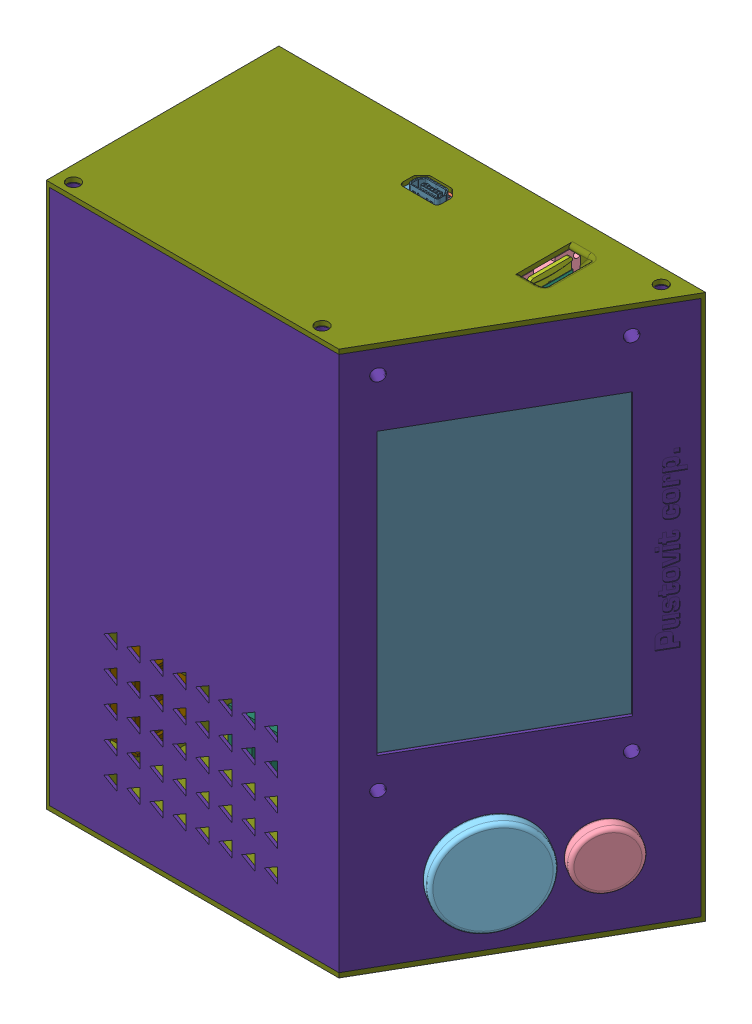
SolidWorks assembly computer, configuration Default. Lengths in mm.
Overall size (117.11 142.67 60.8).
166 component instances, 59 part files, 42 mates.
Components (placement in the parent):
- Arduino Sensor Board V1-1: Arduino Sensor Board V1 [По умолчанию] at (-9.625 26.58 9.294) x (-1 0 0) z (0 1 0) size (53.65 20.91 58.16)
- NUCLEO-F4-1: NUCLEO-F4 [По умолчанию] at origin size (70 83.97 20.27)
  - NUCLEO-F411RE_PCB_VarsayВЌlan-1: NUCLEO-F411RE_PCB_VarsayВЌlan [По умолчанию] at origin size (70 82.5 1.5)
  - NUCLEO-F411RE_PCB_HOLEs_VarsayВЌlan-1: NUCLEO-F411RE_PCB_HOLEs_VarsayВЌlan [По умолчанию] at origin size (65.28 79.87 1.57)
  - NUCLEO-F411RE_PCB_TOP_Pads_VarsayВЌlan-1: NUCLEO-F411RE_PCB_TOP_Pads_VarsayВЌlan [По умолчанию] at origin size (59.94 77.1 0.04)
  - NUCLEO-F411RE_PCB_TOP_Solder_VarsayВЌlan-1: NUCLEO-F411RE_PCB_TOP_Solder_VarsayВЌlan [По умолчанию] at origin size (69.8 82.3 0.05)
  - NUCLEO-F411RE_PCB_BOTTOM_Pads_VarsayВЌlan-1: NUCLEO-F411RE_PCB_BOTTOM_Pads_VarsayВЌlan [По умолчанию] at origin size (31.1 70.87 0.04)
  - NUCLEO-F411RE_PCB_BOTTOM_Solder_VarsayВЌlan-1: NUCLEO-F411RE_PCB_BOTTOM_Solder_VarsayВЌlan [По умолчанию] at origin size (69.8 82.3 0.04)
  - NUCLEO-F411RE_PCB_TOP_Overlay_VarsayВЌlan-1: NUCLEO-F411RE_PCB_TOP_Overlay_VarsayВЌlan [По умолчанию] at origin size (68.11 77.69 0.03)
  - NUCLEO-F411RE_PCB_TOP_Designators_VarsayВЌlan-1: NUCLEO-F411RE_PCB_TOP_Designators_VarsayВЌlan [По умолчанию] at origin size (66.31 79.66 0.03)
  - NUCLEO-F411RE_PCB_BOTTOM_Overlay_VarsayВЌlan-1: NUCLEO-F411RE_PCB_BOTTOM_Overlay_VarsayВЌlan [По умолчанию] at origin size (40.14 80.79 0.03)
  - SAMTEC_SSQ-106-01-G-S_for_NUCLEO_VarsayВЌlan-1: SAMTEC_SSQ-106-01-G-S_for_NUCLEO_VarsayВЌlan [По умолчанию] at (-33.02 8.89 0.785) x (0 1 0) z (1 0 0) size (15.75 11.15 2.41)
  - SAMTEC_SSQ-108-01-G-S_for_NUCLEO_VarsayВЌlan-1: SAMTEC_SSQ-108-01-G-S_for_NUCLEO_VarsayВЌlan [По умолчанию] at (-33.02 29.21 0.785) x (0 1 0) z (1 0 0) size (20.83 11.15 2.41)
  - SAMTEC_SSQ-110-01-G-S_for_NUCLEO_VarsayВЌlan-1: SAMTEC_SSQ-110-01-G-S_for_NUCLEO_VarsayВЌlan [По умолчанию] at (15.24 35.814 0.785) x (0 1 0) z (1 0 0) size (25.91 11.15 2.41)
  - MOLEX_0678038020_for_NUCLEO-1: MOLEX_0678038020_for_NUCLEO [По умолчанию] at (3.1721 75.2975 0.785) x (-1 0 0) z (0 1 0) size (9.9 4.95 9)
  - SAMTEC_TSW-119-07-T-D_for_NUCLEO_VarsayВЌlan-1: SAMTEC_TSW-119-07-T-D_for_NUCLEO_VarsayВЌlan [По умолчанию] at (-39.37 25.4 0.785) x (0 -1 0) z (-1 0 0) size (48.26 17.95 5.08)
  - SAMTEC_TSW-102-07-T-S_for_NUCLEO_VarsayВЌlan-1: SAMTEC_TSW-102-07-T-S_for_NUCLEO_VarsayВЌlan [По умолчанию] at (-40.64 74.93 0.785) x (0 1 0) z (1 0 0) size (5.08 10.92 2.54)
  - SAMTEC_TSW-103-07-T-S_for_NUCLEO_VarsayВЌlan-1: SAMTEC_TSW-103-07-T-S_for_NUCLEO_VarsayВЌlan [По умолчанию] at (1.905 45.085 0.785) x (1 0 0) z (0 -1 0) size (7.62 10.92 2.54)
  - SAMTEC_TSW-104-07-T-S_for_NUCLEO_VarsayВЌlan-1: SAMTEC_TSW-104-07-T-S_for_NUCLEO_VarsayВЌlan [По умолчанию] at (-21.59 73.66 0.785) x (0 1 0) z (1 0 0) size (10.16 10.92 2.54)
  - SAMTEC_TSW-106-07-T-S_for_NUCLEO_VarsayВЌlan-1: SAMTEC_TSW-106-07-T-S_for_NUCLEO_VarsayВЌlan [По умолчанию] at (-35.56 64.77 0.785) x (0 1 0) z (1 0 0) size (15.24 10.92 2.54)
  - MOLEX_90059-0007-1: MOLEX_90059-0007 [По умолчанию] at (-21.59 76.2 5.75) x (0 1 0) z (1 0 0) size (5.1 4.85 2.54)
  - ST_STM32F411RET6_VarsayВЌlan-1: ST_STM32F411RET6_VarsayВЌlan [По умолчанию] at (-11.4265 21.5935 0.785) x (-1 0 0) z (0 0 -1) size (12 12 1.61)
  - ST_STM32F103CBT6_VarsayВЌlan-1: ST_STM32F103CBT6_VarsayВЌlan [По умолчанию] at (-8.89 64.77 0.785) x (1 0 0) z (0 -1 0) size (9 1.61 9)
  - ESWITCH_TL3301SPF160QGBLK_VarsayВЌlan-1: ESWITCH_TL3301SPF160QGBLK_VarsayВЌlan [По умолчанию] at (-0.635 50.8 0.785) x (0 -1 0) z (-1 0 0) size (6.01 10.7 10)
  - ESWITCH_TL3301SPF160QGBLU_VarsayВЌlan-1: ESWITCH_TL3301SPF160QGBLU_VarsayВЌlan [По умолчанию] at (-17.145 50.8 0.785) x (0 1 0) z (1 0 0) size (6.01 10.7 10)
  - ST_STS7PF30L_VarsayВЌlan-1: ST_STS7PF30L_VarsayВЌlan [По умолчанию] at (17.145 60.325 0.785) x (-1 0 0) z (0 1 0) size (4.91 1.76 6)
  - ABRACON_ABL-8-1: ABRACON_ABL-8 [По умолчанию] at (-18.41 63.4908 0.785) x (0 -1 0) z (-1 0 0) size (11.5 5.59 5)
  - ST_LD1117S50TR_VarsayВЌlan-1: ST_LD1117S50TR_VarsayВЌlan [По умолчанию] at (-14.6685 43.18 0.785) x (0 -1 0) z (-1 0 0) size (6.51 1.91 7)
  - ST_LD39050PU33R_VarsayВЌlan-1: ST_LD39050PU33R_VarsayВЌlan [По умолчанию] at (1.905 40.64 0.785) x (0 1 0) z (1 0 0) size (3.01 1.01 3.01)
  - ST_LD3985M33R_VarsayВЌlan-1: ST_LD3985M33R_VarsayВЌlan [По умолчанию] at (7.62 63.5 0.785) x (1 0 0) z (0 -1 0) size (2.96 1.46 2.8)
  - KEMET_T491B106K025AT_VarsayВЌlan-1: KEMET_T491B106K025AT_VarsayВЌlan [По умолчанию] at (-22.86 41.275 0.785) x (0 -1 0) z (-1 0 0) size (2.81 1.91 3.5)
  - ST_STPS2L30A_VarsayВЌlan-1: ST_STPS2L30A_VarsayВЌlan [По умолчанию] at (-22.86 45.085 0.785) x (0 1 0) z (1 0 0) size (2.59 2.31 5.07)
  - KEMET_T491A106K006AT7280_VarsayВЌlan-1: KEMET_T491A106K006AT7280_VarsayВЌlan [По умолчанию] at (-8.255 43.053 0.785) x (1 0 0) z (0 -1 0) size (1.61 1.61 3.2)
  - ABRACON_ABS25-32-1: ABRACON_ABS25-32 [По умолчанию] at (-23.495 6.35 0.785) x (1 0 0) z (0 -1 0) size (8 2.67 4)
  - LUMEX_SML-LX2835IGC-TR-1: LUMEX_SML-LX2835IGC-TR [По умолчанию] at (16.51 73.66 0.785) x (1 0 0) z (0 -1 0) size (2.7 1.8 3.5)
  - ST_BAT60JFILM_VarsayВЌlan-1: ST_BAT60JFILM_VarsayВЌlan [По умолчанию] at (-31.115 71.12 0.785) x (0 -1 0) z (-1 0 0) size (1.29 1.18 2.5)
  - NXP_BC847B,215-1: NXP_BC847B,215 [По умолчанию] at (12.065 64.135 0.785) x (0 -1 0) z (-1 0 0) size (2.9 1.11 2.43)
  - YAGEO_CC0805KKX7R7BB225-1: YAGEO_CC0805KKX7R7BB225 [По умолчанию] at (0.127 23.495 0.785) x (0 -1 0) z (-1 0 0) size (1.59 1.29 4.06)
  - YAGEO_RC0603JR-070RL-1: YAGEO_RC0603JR-070RL [По умолчанию] at (17.145 67.945 0.785) x (1 0 0) z (0 -1 0) size (0.8 0.55 2.16)
  - YAGEO_CC0603KRX7R7BB104-1: YAGEO_CC0603KRX7R7BB104 [По умолчанию] at (-11.43 73.025 0.785) x (1 0 0) z (0 -1 0) size (0.8 0.8 2.16)
  - SAMTEC_SSQ-108-01-G-S_for_NUCLEO_VarsayВЌlan-2: SAMTEC_SSQ-108-01-G-S_for_NUCLEO_VarsayВЌlan [По умолчанию] at (15.24 11.43 0.785) x (0 1 0) z (1 0 0) size (20.83 11.15 2.41)
  - SAMTEC_TSW-119-07-T-D_for_NUCLEO_VarsayВЌlan-2: SAMTEC_TSW-119-07-T-D_for_NUCLEO_VarsayВЌlan [По умолчанию] at (21.59 25.4 0.785) x (0 -1 0) z (-1 0 0) size (48.26 17.95 5.08)
  - SAMTEC_TSW-102-07-T-S_for_NUCLEO_VarsayВЌlan-2: SAMTEC_TSW-102-07-T-S_for_NUCLEO_VarsayВЌlan [По умолчанию] at (-31.75 59.055 0.785) x (0 -1 0) z (-1 0 0) size (5.08 10.92 2.54)
  - SAMTEC_TSW-102-07-T-S_for_NUCLEO_VarsayВЌlan-3: SAMTEC_TSW-102-07-T-S_for_NUCLEO_VarsayВЌlan [По умолчанию] at (-9.525 77.47 0.785) x (1 0 0) z (0 -1 0) size (5.08 10.92 2.54)
  - SAMTEC_TSW-102-07-T-S_for_NUCLEO_VarsayВЌlan-4: SAMTEC_TSW-102-07-T-S_for_NUCLEO_VarsayВЌlan [По умолчанию] at (-9.525 38.735 0.785) x (1 0 0) z (0 -1 0) size (5.08 10.92 2.54)
  - SAMTEC_TSW-102-07-T-S_for_NUCLEO_VarsayВЌlan-5: SAMTEC_TSW-102-07-T-S_for_NUCLEO_VarsayВЌlan [По умолчанию] at (22.86 74.93 0.785) x (0 -1 0) z (-1 0 0) size (5.08 10.92 2.54)
  - MOLEX_90059-0007-2: MOLEX_90059-0007 [По умолчанию] at (-21.59 71.12 5.75) x (0 -1 0) z (-1 0 0) size (5.1 4.85 2.54)
  - MOLEX_90059-0007-3: MOLEX_90059-0007 [По умолчанию] at (3.175 45.085 5.75) x (-1 0 0) z (0 1 0) size (5.1 4.85 2.54)
  - ST_BAT60JFILM_VarsayВЌlan-2: ST_BAT60JFILM_VarsayВЌlan [По умолчанию] at (7.62 69.85 0.785) x (0 -1 0) z (-1 0 0) size (1.29 1.18 2.5)
  - ST_BAT60JFILM_VarsayВЌlan-3: ST_BAT60JFILM_VarsayВЌlan [По умолчанию] at (10.795 59.69 0.785) x (1 0 0) z (0 -1 0) size (1.29 1.18 2.5)
  - YAGEO_RC0603JR-070RL-2: YAGEO_RC0603JR-070RL [По умолчанию] at (15.875 67.945 0.785) x (1 0 0) z (0 -1 0) size (0.8 0.55 2.16)
  - YAGEO_RC0603JR-070RL-3: YAGEO_RC0603JR-070RL [По умолчанию] at (14.605 67.945 0.785) x (1 0 0) z (0 -1 0) size (0.8 0.55 2.16)
  - YAGEO_RC0603JR-070RL-4: YAGEO_RC0603JR-070RL [По умолчанию] at (13.335 67.945 0.785) x (1 0 0) z (0 -1 0) size (0.8 0.55 2.16)
  - YAGEO_RC0603JR-070RL-5: YAGEO_RC0603JR-070RL [По умолчанию] at (12.065 67.945 0.785) x (1 0 0) z (0 -1 0) size (0.8 0.55 2.16)
  - YAGEO_RC0603JR-070RL-6: YAGEO_RC0603JR-070RL [По умолчанию] at (10.795 67.945 0.785) x (1 0 0) z (0 -1 0) size (0.8 0.55 2.16)
  - YAGEO_RC0603JR-070RL-7: YAGEO_RC0603JR-070RL [По умолчанию] at (12.7 59.7535 0.785) x (1 0 0) z (0 -1 0) size (0.8 0.55 2.16)
  - YAGEO_RC0603JR-070RL-8: YAGEO_RC0603JR-070RL [По умолчанию] at (4.445 67.945 0.785) x (1 0 0) z (0 -1 0) size (0.8 0.55 2.16)
  - YAGEO_RC0603JR-070RL-9: YAGEO_RC0603JR-070RL [По умолчанию] at (3.175 67.945 0.785) x (1 0 0) z (0 -1 0) size (0.8 0.55 2.16)
  - YAGEO_RC0603JR-070RL-10: YAGEO_RC0603JR-070RL [По умолчанию] at (1.905 67.945 0.785) x (1 0 0) z (0 -1 0) size (0.8 0.55 2.16)
  - YAGEO_RC0603JR-070RL-11: YAGEO_RC0603JR-070RL [По умолчанию] at (0 67.945 0.785) x (1 0 0) z (0 -1 0) size (0.8 0.55 2.16)
  - YAGEO_RC0603JR-070RL-12: YAGEO_RC0603JR-070RL [По умолчанию] at (-6.985 73.025 0.785) x (1 0 0) z (0 -1 0) size (0.8 0.55 2.16)
  - YAGEO_RC0603JR-070RL-13: YAGEO_RC0603JR-070RL [По умолчанию] at (-8.255 73.025 0.785) x (1 0 0) z (0 -1 0) size (0.8 0.55 2.16)
  - YAGEO_RC0603JR-070RL-14: YAGEO_RC0603JR-070RL [По умолчанию] at (-9.525 73.025 0.785) x (1 0 0) z (0 -1 0) size (0.8 0.55 2.16)
  - YAGEO_RC0603JR-070RL-15: YAGEO_RC0603JR-070RL [По умолчанию] at (-14.605 73.025 0.785) x (1 0 0) z (0 -1 0) size (0.8 0.55 2.16)
  - YAGEO_RC0603JR-070RL-16: YAGEO_RC0603JR-070RL [По умолчанию] at (-31.115 73.025 0.785) x (0 -1 0) z (-1 0 0) size (0.8 0.55 2.16)
  - YAGEO_RC0603JR-070RL-17: YAGEO_RC0603JR-070RL [По умолчанию] at (-31.115 69.215 0.785) x (0 -1 0) z (-1 0 0) size (0.8 0.55 2.16)
  - YAGEO_RC0603JR-070RL-18: YAGEO_RC0603JR-070RL [По умолчанию] at (-31.115 67.31 0.785) x (0 -1 0) z (-1 0 0) size (0.8 0.55 2.16)
  - YAGEO_RC0603JR-070RL-19: YAGEO_RC0603JR-070RL [По умолчанию] at (-31.115 65.405 0.785) x (0 -1 0) z (-1 0 0) size (0.8 0.55 2.16)
  - YAGEO_RC0603JR-070RL-20: YAGEO_RC0603JR-070RL [По умолчанию] at (-31.115 63.5 0.785) x (0 -1 0) z (-1 0 0) size (0.8 0.55 2.16)
  - YAGEO_RC0603JR-070RL-21: YAGEO_RC0603JR-070RL [По умолчанию] at (-25.4 64.77 0.785) x (0 -1 0) z (-1 0 0) size (0.8 0.55 2.16)
  - YAGEO_RC0603JR-070RL-22: YAGEO_RC0603JR-070RL [По умолчанию] at (-25.4 63.5 0.785) x (0 -1 0) z (-1 0 0) size (0.8 0.55 2.16)
  - YAGEO_RC0603JR-070RL-23: YAGEO_RC0603JR-070RL [По умолчанию] at (-25.4 62.23 0.785) x (0 -1 0) z (-1 0 0) size (0.8 0.55 2.16)
  - YAGEO_RC0603JR-070RL-24: YAGEO_RC0603JR-070RL [По умолчанию] at (-25.4 60.96 0.785) x (0 -1 0) z (-1 0 0) size (0.8 0.55 2.16)
  - YAGEO_RC0603JR-070RL-25: YAGEO_RC0603JR-070RL [По умолчанию] at (-15.875 11.43 0.785) x (1 0 0) z (0 -1 0) size (0.8 0.55 2.16)
  - YAGEO_RC0603JR-070RL-26: YAGEO_RC0603JR-070RL [По умолчанию] at (-14.605 11.43 0.785) x (1 0 0) z (0 -1 0) size (0.8 0.55 2.16)
  - YAGEO_RC0603JR-070RL-27: YAGEO_RC0603JR-070RL [По умолчанию] at (-22.225 18.415 0.785) x (1 0 0) z (0 -1 0) size (0.8 0.55 2.16)
  - YAGEO_RC0603JR-070RL-28: YAGEO_RC0603JR-070RL [По умолчанию] at (-20.955 32.385 0.785) x (0 -1 0) z (-1 0 0) size (0.8 0.55 2.16)
  - YAGEO_RC0603JR-070RL-29: YAGEO_RC0603JR-070RL [По умолчанию] at (-8.89 51.435 0.785) x (0 -1 0) z (-1 0 0) size (0.8 0.55 2.16)
  - YAGEO_RC0603JR-070RL-30: YAGEO_RC0603JR-070RL [По умолчанию] at (-8.89 47.625 0.785) x (0 -1 0) z (-1 0 0) size (0.8 0.55 2.16)
  - YAGEO_RC0603JR-070RL-31: YAGEO_RC0603JR-070RL [По умолчанию] at (3.81 36.83 0.785) x (0 -1 0) z (-1 0 0) size (0.8 0.55 2.16)
  - YAGEO_RC0603JR-070RL-32: YAGEO_RC0603JR-070RL [По умолчанию] at (0 63.5 0.785) x (0 -1 0) z (-1 0 0) size (0.8 0.55 2.16)
  - YAGEO_RC0603JR-070RL-33: YAGEO_RC0603JR-070RL [По умолчанию] at (0 62.23 0.785) x (0 -1 0) z (-1 0 0) size (0.8 0.55 2.16)
  - YAGEO_CC0603KRX7R7BB104-2: YAGEO_CC0603KRX7R7BB104 [По умолчанию] at (-1.905 67.945 0.785) x (1 0 0) z (0 -1 0) size (0.8 0.8 2.16)
  - YAGEO_CC0603KRX7R7BB104-3: YAGEO_CC0603KRX7R7BB104 [По умолчанию] at (5.08 62.865 0.785) x (1 0 0) z (0 -1 0) size (0.8 0.8 2.16)
  - YAGEO_CC0603KRX7R7BB104-4: YAGEO_CC0603KRX7R7BB104 [По умолчанию] at (6.985 59.69 0.785) x (1 0 0) z (0 -1 0) size (0.8 0.8 2.16)
  - YAGEO_CC0603KRX7R7BB104-5: YAGEO_CC0603KRX7R7BB104 [По умолчанию] at (8.89 59.69 0.785) x (1 0 0) z (0 -1 0) size (0.8 0.8 2.16)
  - YAGEO_CC0603KRX7R7BB104-6: YAGEO_CC0603KRX7R7BB104 [По умолчанию] at (-21.59 62.23 0.785) x (1 0 0) z (0 -1 0) size (0.8 0.8 2.16)
  - YAGEO_CC0603KRX7R7BB104-7: YAGEO_CC0603KRX7R7BB104 [По умолчанию] at (-21.59 64.77 0.785) x (1 0 0) z (0 -1 0) size (0.8 0.8 2.16)
  - YAGEO_CC0603KRX7R7BB104-8: YAGEO_CC0603KRX7R7BB104 [По умолчанию] at (-15.24 63.5 0.785) x (1 0 0) z (0 -1 0) size (0.8 0.8 2.16)
  - YAGEO_CC0603KRX7R7BB104-9: YAGEO_CC0603KRX7R7BB104 [По умолчанию] at (-6.35 58.42 0.785) x (0 -1 0) z (-1 0 0) size (0.8 0.8 2.16)
  - YAGEO_CC0603KRX7R7BB104-10: YAGEO_CC0603KRX7R7BB104 [По умолчанию] at (-8.89 53.34 0.785) x (0 -1 0) z (-1 0 0) size (0.8 0.8 2.16)
  - YAGEO_CC0603KRX7R7BB104-11: YAGEO_CC0603KRX7R7BB104 [По умолчанию] at (-8.89 49.53 0.785) x (0 -1 0) z (-1 0 0) size (0.8 0.8 2.16)
  - YAGEO_CC0603KRX7R7BB104-12: YAGEO_CC0603KRX7R7BB104 [По умолчанию] at (-2.54 40.64 0.785) x (1 0 0) z (0 -1 0) size (0.8 0.8 2.16)
  - YAGEO_CC0603KRX7R7BB104-13: YAGEO_CC0603KRX7R7BB104 [По умолчанию] at (-1.27 40.64 0.785) x (1 0 0) z (0 -1 0) size (0.8 0.8 2.16)
  - YAGEO_CC0603KRX7R7BB104-14: YAGEO_CC0603KRX7R7BB104 [По умолчанию] at (5.08 40.64 0.785) x (1 0 0) z (0 -1 0) size (0.8 0.8 2.16)
  - YAGEO_CC0603KRX7R7BB104-15: YAGEO_CC0603KRX7R7BB104 [По умолчанию] at (6.35 40.64 0.785) x (1 0 0) z (0 -1 0) size (0.8 0.8 2.16)
  - YAGEO_CC0603KRX7R7BB104-16: YAGEO_CC0603KRX7R7BB104 [По умолчанию] at (-0.6033 27.94 0.785) x (0 -1 0) z (-1 0 0) size (0.8 0.8 2.16)
  - YAGEO_CC0603KRX7R7BB104-17: YAGEO_CC0603KRX7R7BB104 [По умолчанию] at (-17.145 32.385 0.785) x (1 0 0) z (0 -1 0) size (0.8 0.8 2.16)
  - YAGEO_CC0603KRX7R7BB104-18: YAGEO_CC0603KRX7R7BB104 [По умолчанию] at (-20.32 18.415 0.785) x (1 0 0) z (0 -1 0) size (0.8 0.8 2.16)
  - YAGEO_CC0603KRX7R7BB104-19: YAGEO_CC0603KRX7R7BB104 [По умолчанию] at (-17.145 11.43 0.785) x (1 0 0) z (0 -1 0) size (0.8 0.8 2.16)
  - YAGEO_CC0603KRX7R7BB104-20: YAGEO_CC0603KRX7R7BB104 [По умолчанию] at (0 17.78 0.785) x (0 -1 0) z (-1 0 0) size (0.8 0.8 2.16)
  - YAGEO_CC0603KRX7R7BB104-21: YAGEO_CC0603KRX7R7BB104 [По умолчанию] at (-8.636 12.192 0.785) x (0 -1 0) z (-1 0 0) size (0.8 0.8 2.16)
  - YAGEO_CC0603KRX7R7BB104-22: YAGEO_CC0603KRX7R7BB104 [По умолчанию] at (-19.685 2.794 0.785) x (0 -1 0) z (-1 0 0) size (0.8 0.8 2.16)
  - YAGEO_CC0603KRX7R7BB104-23: YAGEO_CC0603KRX7R7BB104 [По умолчанию] at (-19.685 10.795 0.785) x (0 -1 0) z (-1 0 0) size (0.8 0.8 2.16)
- Product_TF Micro SD Card Memory Modul Arduino-1: Product_TF Micro SD Card Memory Modul Arduino [Default] at (32.8 80 5.215) x (0 0 1) z (1 0 0) size (24 45.73 7.3)
  - PCB-1: PCB [По умолчанию] at origin size (24 41.8 1.25)
  - 1 Pin 2.54 mm Right Angle Single Row Pin Header Male 90 degrees Needle Connector-1: 1 Pin 2.54 mm Right Angle Single Row Pin Header Male 90 degrees Needle Connector [По умолчанию] at (-6.375 38.55 -1.71) x (0 1 0) z (0 0 1) size (8.45 2.54 7.3)
  - 1 Pin 2.54 mm Right Angle Single Row Pin Header Male 90 degrees Needle Connector-2: 1 Pin 2.54 mm Right Angle Single Row Pin Header Male 90 degrees Needle Connector [По умолчанию] at (-3.835 38.55 -1.71) x (0 1 0) z (0 0 1) size (8.45 2.54 7.3)
  - 1 Pin 2.54 mm Right Angle Single Row Pin Header Male 90 degrees Needle Connector-3: 1 Pin 2.54 mm Right Angle Single Row Pin Header Male 90 degrees Needle Connector [По умолчанию] at (-1.295 38.55 -1.71) x (0 1 0) z (0 0 1) size (8.45 2.54 7.3)
  - 1 Pin 2.54 mm Right Angle Single Row Pin Header Male 90 degrees Needle Connector-4: 1 Pin 2.54 mm Right Angle Single Row Pin Header Male 90 degrees Needle Connector [По умолчанию] at (1.245 38.55 -1.71) x (0 1 0) z (0 0 1) size (8.45 2.54 7.3)
  - 1 Pin 2.54 mm Right Angle Single Row Pin Header Male 90 degrees Needle Connector-5: 1 Pin 2.54 mm Right Angle Single Row Pin Header Male 90 degrees Needle Connector [По умолчанию] at (3.785 38.55 -1.71) x (0 1 0) z (0 0 1) size (8.45 2.54 7.3)
  - 1 Pin 2.54 mm Right Angle Single Row Pin Header Male 90 degrees Needle Connector-6: 1 Pin 2.54 mm Right Angle Single Row Pin Header Male 90 degrees Needle Connector [По умолчанию] at (6.325 38.55 -1.71) x (0 1 0) z (0 0 1) size (8.45 2.54 7.3)
  - slot-1: slot [По умолчанию] at (-0.1 9.44 2.1) size (16 15 2.44)
  - sd-1: sd [По умолчанию] at (-45.7851 11.4225 2.13) size (11 15 1.1)
  - nano - reg-1: nano - reg [По умолчанию] at (5.85 28.63 1.25) x (0 -1 0) z (-1 0 0) size (6.5 1.69 8.3)
  - res_603-1: res_603 [По умолчанию] at (-9.4 21.6 1.25) x (0 -1 0) z (-1 0 0) size (1.6 0.5 0.8)
  - res_603-2: res_603 [По умолчанию] at (-7.35 21.6 1.25) x (0 -1 0) z (-1 0 0) size (1.6 0.5 0.8)
  - res_603-3: res_603 [По умолчанию] at (-7.3 34.3 1.25) x (0 -1 0) z (-1 0 0) size (1.6 0.5 0.8)
  - res_603-4: res_603 [По умолчанию] at (-8.8 34.3 1.25) x (0 -1 0) z (-1 0 0) size (1.6 0.5 0.8)
  - cap_603-1: cap_603 [По умолчанию] at (-9.34 32.2 2.05) x (0 1 0) z (0 0 1) size (1.6 0.8 0.8)
  - cap_603-2: cap_603 [По умолчанию] at (7.2 20.55 2.05) x (0 1 0) z (0 0 1) size (1.6 0.8 0.8)
  - cap_603-3: cap_603 [По умолчанию] at (10.8 33.9 2.05) x (0 1 0) z (0 0 1) size (1.6 0.8 0.8)
  - cap_805-1: cap_805 [По умолчанию] at (9.4 20.1 2.05) x (0 1 0) z (0 0 1) size (2.06 1.35 0.82)
  - LVC125A-1: LVC125A [По умолчанию] at (-10.3 28.9 1.25) x (0 -1 0) z (0 0 1) size (6.6 5.2 0.95)
- DIN 5 Connector (Female)-1: DIN 5 Connector (Female) [По умолчанию] at (-50.3 -11.2 32.415) x (0 -1 0) z (-1 0 0) size (29 18.3 17)
- Pantalla Nextion 3.5-1: Pantalla Nextion 3.5 [По умолчанию] at (37.9033 26.95 20.4374) x (0 -1 0) z (0.866025 0 0.5) size (100.5 54.94 11.65)
- DC-DC CC CV Buck Converter Step-down Power Supply Module 7-40V to 1-35V 12A-1: DC-DC CC CV Buck Converter Step-down Power Supply Module 7-40V to 1-35V 12A [00] at (-8 -30 0.715) x (0 -1 0) z (-1 0 0) size (49 24 65)
- Корпус база^computer-1: Корпус база^computer [По умолчанию] at origin size (111.6 142.4 60.8) (virtual)
- Корпус крышка^computer-1: Корпус крышка^computer [По умолчанию] at (0 -61.2 0) x (-1 0 0) z (0 -1 0) size (110.34 60 140) (virtual)
- Power Switch-1: Power Switch [По умолчанию] at (-48.8 -51.2 40.415) x (0 1 0) z (0 0 1) size (21.33 24.14 14.86)
- Pins_place-1: Pins_place [Default] at (-40 43 30.215) x (0 1 0) z (0 0 1) size (70 10.84 30)
  - PIN-1: PIN [По умолчанию] at (24.34 2 3.88) x (0 0 -1) z (1 0 0) size (2.54 10.84 2.54)
  - place-1: place [По умолчанию] at origin size (70 2 30)
  - PIN-2: PIN [По умолчанию] at (24.34 2 1.34) x (0 0 -1) z (1 0 0) size (2.54 10.84 2.54)
  - PIN-3: PIN [По умолчанию] at (24.34 2 -1.2) x (0 0 -1) z (1 0 0) size (2.54 10.84 2.54)
  - PIN-4: PIN [По умолчанию] at (21.8 2 3.88) x (0 0 -1) z (1 0 0) size (2.54 10.84 2.54)
  - PIN-5: PIN [По умолчанию] at (21.8 2 1.34) x (0 0 -1) z (1 0 0) size (2.54 10.84 2.54)
  - PIN-6: PIN [По умолчанию] at (21.8 2 -1.2) x (0 0 -1) z (1 0 0) size (2.54 10.84 2.54)
  - PIN-7: PIN [По умолчанию] at (19.26 2 3.88) x (0 0 -1) z (1 0 0) size (2.54 10.84 2.54)
  - PIN-8: PIN [По умолчанию] at (19.26 2 1.34) x (0 0 -1) z (1 0 0) size (2.54 10.84 2.54)
  - PIN-9: PIN [По умолчанию] at (19.26 2 -1.2) x (0 0 -1) z (1 0 0) size (2.54 10.84 2.54)
  - PIN-10: PIN [По умолчанию] at (16.72 2 3.88) x (0 0 -1) z (1 0 0) size (2.54 10.84 2.54)
  - PIN-11: PIN [По умолчанию] at (16.72 2 1.34) x (0 0 -1) z (1 0 0) size (2.54 10.84 2.54)
  - PIN-12: PIN [По умолчанию] at (16.72 2 -1.2) x (0 0 -1) z (1 0 0) size (2.54 10.84 2.54)
  - PIN-13: PIN [По умолчанию] at (14.18 2 3.88) x (0 0 -1) z (1 0 0) size (2.54 10.84 2.54)
  - PIN-14: PIN [По умолчанию] at (14.18 2 1.34) x (0 0 -1) z (1 0 0) size (2.54 10.84 2.54)
  - PIN-15: PIN [По умолчанию] at (14.18 2 -1.2) x (0 0 -1) z (1 0 0) size (2.54 10.84 2.54)
  - PIN-16: PIN [По умолчанию] at (11.64 2 3.88) x (0 0 -1) z (1 0 0) size (2.54 10.84 2.54)
  - PIN-17: PIN [По умолчанию] at (11.64 2 1.34) x (0 0 -1) z (1 0 0) size (2.54 10.84 2.54)
  - PIN-18: PIN [По умолчанию] at (11.64 2 -1.2) x (0 0 -1) z (1 0 0) size (2.54 10.84 2.54)
  - PIN-19: PIN [По умолчанию] at (9.1 2 3.88) x (0 0 -1) z (1 0 0) size (2.54 10.84 2.54)
  - PIN-20: PIN [По умолчанию] at (9.1 2 1.34) x (0 0 -1) z (1 0 0) size (2.54 10.84 2.54)
  - PIN-21: PIN [По умолчанию] at (9.1 2 -1.2) x (0 0 -1) z (1 0 0) size (2.54 10.84 2.54)
  - PIN-22: PIN [По умолчанию] at (6.56 2 3.88) x (0 0 -1) z (1 0 0) size (2.54 10.84 2.54)
  - PIN-23: PIN [По умолчанию] at (6.56 2 1.34) x (0 0 -1) z (1 0 0) size (2.54 10.84 2.54)
  - PIN-24: PIN [По умолчанию] at (6.56 2 -1.2) x (0 0 -1) z (1 0 0) size (2.54 10.84 2.54)
  - PIN-25: PIN [По умолчанию] at (4.02 2 3.88) x (0 0 -1) z (1 0 0) size (2.54 10.84 2.54)
  - PIN-26: PIN [По умолчанию] at (4.02 2 1.34) x (0 0 -1) z (1 0 0) size (2.54 10.84 2.54)
  - PIN-27: PIN [По умолчанию] at (4.02 2 -1.2) x (0 0 -1) z (1 0 0) size (2.54 10.84 2.54)
  - PIN-28: PIN [По умолчанию] at (1.48 2 3.88) x (0 0 -1) z (1 0 0) size (2.54 10.84 2.54)
  - PIN-29: PIN [По умолчанию] at (1.48 2 1.34) x (0 0 -1) z (1 0 0) size (2.54 10.84 2.54)
  - PIN-30: PIN [По умолчанию] at (1.48 2 -1.2) x (0 0 -1) z (1 0 0) size (2.54 10.84 2.54)
- Button-1: Button [По умолчанию] at (48.508 -41 5.1695) x (0 -1 0) z (-0.5 0 0.866025) size (14.38 11.2 12)
- Button-2: Button [По умолчанию] at (37.508 -41 24.222) x (0 1 0) z (0.5 0 -0.866025) size (14.38 11.2 12)
- ResetBut-1: ResetBut [По умолчанию] at (56.7785 -41 9.9445) x (0 -1 0) z (-0.5 0 0.866025) size (15 5 15)
- StopBut-1: StopBut [По умолчанию] at (45.7785 -41 28.997) x (0 -1 0) z (-0.5 0 0.866025) size (25 5 25)
Mates (geometry in assembly coordinates):
- Совпадение2: coincident anti-aligned: plane of Arduino Sensor Board V1-1 through (-9.6294 26.9555 9.294) normal (0 0 -1); plane of NUCLEO-F4-1/SAMTEC_SSQ-108-01-G-S_for_NUCLEO_VarsayВЌlan-2 through (14.0235 1.006 9.294) normal (0 0 1)
- Концентричный1: concentric aligned: cylinder of Arduino Sensor Board V1-1 through (0 0 9.294) axis (0 0 1) radius 1.75; circle of NUCLEO-F4-1/NUCLEO-F411RE_PCB_HOLEs_VarsayВЌlan-1
- Параллельность1: parallel anti-aligned: plane of Arduino Sensor Board V1-1 through (-34.37 2.11 9.294) normal (-1 0 0); plane of NUCLEO-F4-1/SAMTEC_SSQ-106-01-G-S_for_NUCLEO_VarsayВЌlan-1 through (-33.528 2.022 1.283) normal (1 0 0)
- Совпадение6: coincident aligned: plane of NUCLEO-F4-1/NUCLEO-F411RE_PCB_BOTTOM_Solder_VarsayВЌlan-1 through (26.018 -2.408 -0.785) normal (0 0 -1); plane of DC-DC CC CV Buck Converter Step-down Power Supply Module 7-40V to 1-35V 12A-1 through (-8 -30 -0.785) normal (0 0 -1)
- Расстояние1: distance = 30 mm anti-aligned: plane of DC-DC CC CV Buck Converter Step-down Power Supply Module 7-40V to 1-35V 12A-1 through (-8 -30 0.715) normal (0 -1 0); plane of NUCLEO-F4-1 through (0 0 0) normal (0 1 0)
- Расстояние2: distance = 8 mm anti-aligned: plane of NUCLEO-F4-1 through (0 0 0) normal (1 0 0); plane of DC-DC CC CV Buck Converter Step-down Power Supply Module 7-40V to 1-35V 12A-1 through (-8 -30 0.715) normal (-1 0 0)
- Совпадение9: coordinate: point of NUCLEO-F4-1
- На месте2: in place: plane of ? through (0 0 0) normal (0 0 1); moOrthogonalPlaneRef_w of ? through (0 0 0) normal (0 1 0); plane of ? through (0 0 0) normal (1 0 0); unknown of ?
- Совпадение17: coincident aligned: 
- Совпадение18: coincident aligned: plane of Корпус база^computer-1 through (0 0 0) normal (0 1 0)
- Совпадение19: coincident anti-aligned: plane of Корпус база^computer-1 through (0 0 0) normal (1 0 0)
- Расстояние5: distance = 1 mm aligned: plane of Корпус база^computer-1 through (62.8 81.2 -9.585) normal (0.866025 0 0.5); plane of Pantalla Nextion 3.5-1 through (29.6197 -14.68 45.8849) normal (0.866025 0 0.5)
- Расстояние3: distance = 4 mm aligned: plane of Корпус база^computer-1 through (20.1678 81.2 -9.585) normal (0 1 0); plane of Pantalla Nextion 3.5-1 through (26.5539 77.2 43.295) normal (0 1 0)
- Расстояние4: distance = 12 mm: line of Корпус база^computer-1 through (62.3381 -60 -8.785) axis (0 1 0); line of Pantalla Nextion 3.5-1 through (51.6383 75.2 -3.3524) axis (0 -1 0)
- На месте3: in place: plane of ? through (20.1678 -60.8 -9.585) normal (0 -1 0); plane of ? through (0 -60.8 0) normal (0 -1 0); plane of ? through (20.1678 -60.8 -9.585) normal (0 -1 0); plane of ? through (0 -60.8 0) normal (0 0 -1); plane of ? through (20.1678 -60.8 -9.585) normal (0 -1 0); plane of ? through (0 -60.8 0) normal (-1 0 0); plane of ? through (20.1678 -61.2 -9.585) normal (0 -1 0); unknown of Корпус крышка^computer-1
- Совпадение20: coincident aligned: plane of Корпус база^computer-1; plane of Корпус крышка^computer-1
- Совпадение21: coincident aligned: moOrthogonalPlaneRef_w of Корпус база^computer-1 through (0 -61.2 0) normal (0 0 -1); plane of Корпус крышка^computer-1 through (0 -61.2 0) normal (0 0 -1)
- Совпадение22: coincident anti-aligned: moOrthogonalPlaneRef_w of Корпус база^computer-1 through (0 -61.2 0) normal (1 0 0); plane of Корпус крышка^computer-1 through (0 -61.2 0) normal (-1 0 0)
- Совпадение14: coincident anti-aligned: plane of DIN 5 Connector (Female)-1 through (-48.8 -11.2 32.415) normal (1 0 0); plane of Корпус база^computer-1 through (-48.8 2.6922 -9.585) normal (-1 0 0)
- Расстояние6: distance = 42 mm anti-aligned: plane of DIN 5 Connector (Female)-1 through (-50.3 -11.2 32.415) normal (0 0 1); plane of Корпус база^computer-1 through (0 0 -9.585) normal (0 0 -1)
- Расстояние7: distance = 50 mm aligned: plane of DIN 5 Connector (Female)-1 through (-50.3 -11.2 32.415) normal (0 -1 0); plane of Корпус база^computer-1 through (20.1678 -61.2 -9.585) normal (0 -1 0)
- Совпадение17: coincident anti-aligned: plane of Корпус база^computer-1 through (-48.8 2.6922 -9.585) normal (-1 0 0); plane of Power Switch-1 through (-48.8 -51.2 40.415) normal (1 0 0)
- Расстояние10: distance = 10 mm anti-aligned: plane of Power Switch-1 through (-48.8 -51.2 40.415) normal (0 1 0); plane of Корпус база^computer-1 through (20.1678 -61.2 -9.585) normal (0 -1 0)
- Расстояние11: distance = 50 mm anti-aligned: plane of Power Switch-1 through (-48.8 -51.2 40.415) normal (0 0 1); plane of Корпус база^computer-1 through (0 0 -9.585) normal (0 0 -1)
- Совпадение19: coincident anti-aligned: plane of Product_TF Micro SD Card Memory Modul Arduino-1/PCB-1 through (32.8 80 5.215) normal (0 1 0); plane of Корпус база^computer-1 through (0 80 51.215) normal (0 -1 0)
- Совпадение20: coincident anti-aligned: plane of Product_TF Micro SD Card Memory Modul Arduino-1/PCB-1 through (32.8 80 5.215) normal (-1 0 0); plane of Корпус база^computer-1 through (32.8 0 -4.785) normal (1 0 0)
- Расстояние12: distance = 2 mm anti-aligned: plane of Корпус база^computer-1 through (0 0 -8.785) normal (0 0 1); plane of Product_TF Micro SD Card Memory Modul Arduino-1/PCB-1 through (32.8 80 -6.785) normal (0 0 -1)
- Расстояние13: distance = 6 mm anti-aligned: plane of Pins_place-1/place-1 through (-42 43 30.215) normal (-1 0 0); plane of Корпус база^computer-1 through (-48 0 51.215) normal (1 0 0)
- Расстояние14: distance = 2 mm anti-aligned: plane of Корпус база^computer-1 through (0 80 51.215) normal (0 -1 0); plane of Pins_place-1/place-1 through (-42 78 45.215) normal (0 1 0)
- Расстояние15: distance = 54 mm aligned: plane of Корпус база^computer-1 through (0 0 -8.785) normal (0 0 1); plane of Pins_place-1/place-1 through (-42 78 45.215) normal (0 0 1)
- Совпадение21: coincident anti-aligned: plane of Корпус база^computer-1 through (27.9458 -37 40.7842) normal (0.866025 0 0.5); plane of Button-1 through (48.508 -41 5.1695) normal (-0.866025 0 -0.5)
- Расстояние16: distance = 13 mm: plane of Button-1 through (54.4092 -47 1.6483) normal (0.5 0 -0.866025); line of Корпус база^computer-1 through (62.3381 -60 -8.785) axis (0 1 0)
- Ширина1: width anti-aligned: plane of Корпус база^computer-1 through (0 -37 0) normal (0 1 0); plane of Button-1 through (0 -45 0) normal (0 -1 0); plane of Корпус база^computer-1 through (48.4092 -47 12.0406) normal (0 -1 0); plane of Button-1 through (48.4092 -35 12.0406) normal (0 1 0)
- Совпадение23: coincident anti-aligned: plane of Корпус база^computer-1 through (27.9458 -37 40.7842) normal (0.866025 0 0.5); plane of Button-2 through (37.508 -41 24.222) normal (-0.866025 0 -0.5)
- Ширина2: width anti-aligned: plane of Корпус база^computer-1 through (0 -37 0) normal (0 1 0); plane of Button-2 through (0 -45 0) normal (0 -1 0); plane of Корпус база^computer-1 through (43.4092 -47 20.7009) normal (0 -1 0); plane of Button-2 through (43.4092 -35 20.7009) normal (0 1 0)
- Расстояние17: distance = 10 mm anti-aligned: plane of Button-2 through (43.4092 -35 20.7009) normal (0.5 0 -0.866025); plane of Button-1 through (48.4092 -47 12.0406) normal (-0.5 0 0.866025)
- Концентричный2: concentric anti-aligned: cylinder of Button-1 through (55.0465 -41 8.9445) axis (-0.866025 0 -0.5) radius 0.85; cylinder of ResetBut-1 through (55.7393 -41 9.3445) axis (0.866025 0 0.5) radius 7.5
- Параллельность2: parallel aligned: plane of Button-1 through (55.0465 -42.9 8.9445) normal (0 -1 0); plane of ResetBut-1 through (55.0465 -44.1 8.9445) normal (0 -1 0)
- Расстояние18: distance = 0 mm anti-aligned: plane of Button-1 through (55.0465 -41 8.9445) normal (0.866025 0 0.5); plane of ResetBut-1 through (55.0465 -41 8.9445) normal (-0.866025 0 -0.5)
- Концентричный3: concentric anti-aligned: cylinder of Button-2 through (44.0465 -41 27.997) axis (-0.866025 0 -0.5) radius 0.85; cylinder of StopBut-1 through (44.7393 -41 28.397) axis (0.866025 0 0.5) radius 12.5
- Параллельность3: parallel aligned: plane of Button-2 through (44.0465 -42.9 27.997) normal (0 -1 0); plane of StopBut-1 through (44.0465 -44.1 27.997) normal (0 -1 0)
- Совпадение27: coincident anti-aligned: plane of Button-2 through (44.0465 -41 27.997) normal (0.866025 0 0.5); plane of StopBut-1 through (44.0465 -41 27.997) normal (-0.866025 0 -0.5)
